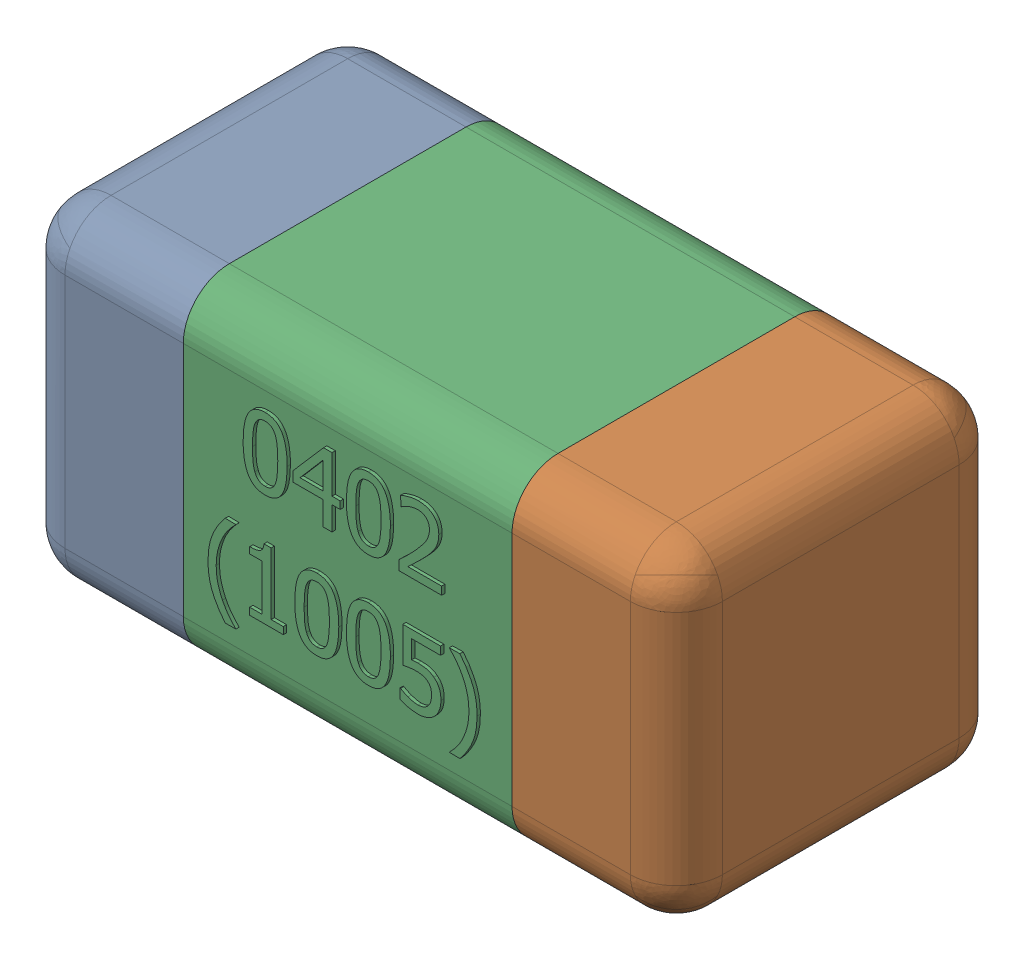
SolidWorks assembly C4, configuration Standard. Lengths in mm.
Overall size (1.01 0.51 0.51).
4 component instances, 3 part files, 0 mates.
Components (placement in the parent):
- C4-subassembly-1-1: C4-subassembly-1 [Standard] at (3.1001 -3.2 0) x (1 0 0) z (0 0 1) size (1.01 0.51 0.51)
  - User Library-0402_Cap-1: User Library-0402_Cap [Standard] at origin size (0.26 0.51 0.51)
  - User Library-0402_Cap-1-1: User Library-0402_Cap-1 [Standard] at origin size (0.26 0.5 0.51)
  - User Library-0402_Cap-2-1: User Library-0402_Cap-2 [Standard] at origin size (0.5 0.5 0.51)
